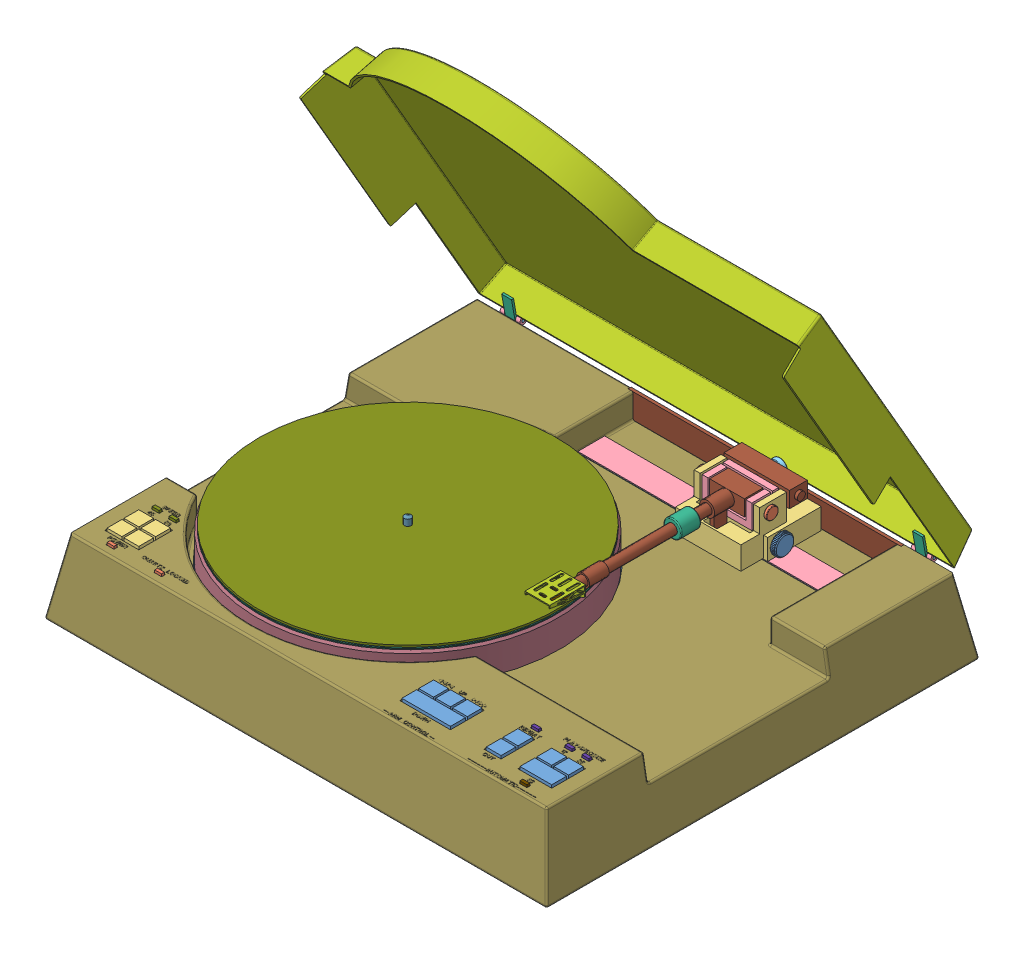
SolidWorks assembly Aptilla_Yamaha_PX-2, configuration Default. Lengths in mm.
Overall size (505.68 446.22 450.35).
80 component instances, 47 part files, 0 mates.
Components (placement in the parent):
- 05_ToneArm_Drive-1: 05_ToneArm_Drive [Default] at origin size (332.22 49 92)
  - 01_Carrier-1: 01_Carrier [Default] at origin size (321 49 83)
    - Roller.1.2-1: Roller.1.2 [Default] at (-301 0 0) size (19 19 29)
    - Roller.1.2-2: Roller.1.2 [Default] at origin size (19 19 29)
    - Roller.1.2-3: Roller.1.2 [Default] at (0 -20 0) size (19 19 29)
    - Roller.1.2-4: Roller.1.2 [Default] at (-301 -20 0) size (19 19 29)
    - Bracket.2-1: Bracket.2 [Default] at (175 0 0) size (20 36.5 33)
    - Wheel.2-1: Wheel.2 [Default] at (118 0 0) size (12 12 5)
    - Wheel.2-2: Wheel.2 [Default] at (248 58.6314 -492.1127) x (1 0 0) z (0 0 -1) size (12 12 5)
    - Wheel.2-3: Wheel.2 [Default] at (248 58.6314 -538.1127) x (1 0 0) z (0 0 -1) size (12 12 5)
    - Belt-1: Belt [Default] at origin size (318 37 27)
    - Carrier-1: Carrier [Default] at (258 0 0) size (150 43.5 64)
    - Wheel.2-4: Wheel.2 [Default] at (118 0 46) size (12 12 5)
    - RailProfile-1: RailProfile [Default] at origin size (321 12.5 83)
  - 02_Drive-1: 02_Drive [Default] at origin size (40.22 41 68)
    - Bracket.1-1: Bracket.1 [Default] at (-126 0 0) size (24 36.5 66)
    - Motor-1: Motor [Default] at origin size (40.22 22 22)
    - Gear.1-1: Gear.1 [Default] at (0 0 1) size (19 19 4)
    - Band-1: Band [Default] at origin size (1.5 20 35)
    - Worm_Axle-1: Worm_Axle [Default] at (10 -2 0) size (30 3 3)
    - Wheel_C-1: Wheel_C [Default] at (-0.5 0 0) size (8 10 10)
    - Axle.1-1: Axle.1 [Default] at origin size (2 2 40)
    - Worm-1: Worm [Default] at (10 -2 0) size (10 6 6)
    - Wheel_B-1: Wheel_B [Default] at (-0.5 0 0) size (4 20 20)
- 02_Controls-1: 02_Controls [Default] at origin size (452 6 60)
  - Controls_B.1-1: Controls_B.1 [Default] at (0 -6 0) size (44.81 6 9.25)
  - Controls_B.3-1: Controls_B.3 [Default] at (0 -6 0) size (155 6 9.25)
  - Controls_B.4-1: Controls_B.4 [Default] at (0 -6 0) size (155 6 9.25)
  - Controls_A.2-1: Controls_A.2 [Default] at (0 -6 0) size (155 6 41.5)
  - Controls_B.2-1: Controls_B.2 [Default] at (0 -6 0) size (71 6 9.25)
  - Controls_A.1-1: Controls_A.1 [Default] at (0 -6 0) size (71 6 41.5)
- 01_Base-1: 01_Base [Default] at origin size (505.68 446.22 450.35)
  - Hinge.1-1: Hinge.1 [Default] at (22 0 0) size (20 39.74 10.42)
    - Hinge_A-1: Hinge_A [Default] at origin size (20 23.8 7)
    - HingePin-1: HingePin [Default] at origin size (20 3 3)
    - Hinge_B-1: Hinge_B [Default] at origin size (10 22.94 10.42)
  - Cover-1: Cover [Default] at (0 298.2735 -73.3934) x (1 0 0) z (0 0.866025 0.5) size (488.72 54.66 402)
  - Support.1-1: Support.1 [Default] at (410 0 85) size (41.04 31.47 41.04)
    - Foot-1: Foot [Default] at (271.8949 582.3157 -214.5011) x (0 -1 0) z (1 0 0) size (31.47 41.04 41.04)
    - Spring-1: Spring [Default] at origin size (28.77 18.41 28.97)
  - Support.1-2: Support.1 [Default] at (410 0 340) size (41.04 31.47 41.04)
    - Foot-1: Foot [Default] at (271.8949 582.3157 -214.5011) x (0 -1 0) z (1 0 0) size (31.47 41.04 41.04)
    - Spring-1: Spring [Default] at origin size (28.77 18.41 28.97)
  - Support.1-3: Support.1 [Default] at (0 0 340) size (41.04 31.47 41.04)
    - Foot-1: Foot [Default] at (271.8949 582.3157 -214.5011) x (0 -1 0) z (1 0 0) size (31.47 41.04 41.04)
    - Spring-1: Spring [Default] at origin size (28.77 18.41 28.97)
  - Support.1-4: Support.1 [Default] at origin size (41.04 31.47 41.04)
    - Foot-1: Foot [Default] at (271.8949 582.3157 -214.5011) x (0 -1 0) z (1 0 0) size (31.47 41.04 41.04)
    - Spring-1: Spring [Default] at origin size (28.77 18.41 28.97)
  - Bottom-1: Bottom [Default] at origin size (474 26.57 402)
  - Plate-1: Plate [Default] at (0 -49.3225 -19.2435) x (1 0 0) z (0 -0.173648 0.984808) size (275 30.53 3)
  - Base_2-1: Base_2 [Default] at origin size (505.68 76.03 435.77)
  - Hinge.1-2: Hinge.1 [Default] at (-392 0 0) size (20 39.74 10.42)
    - Hinge_A-1: Hinge_A [Default] at origin size (20 23.8 7)
    - HingePin-1: HingePin [Default] at origin size (20 3 3)
    - Hinge_B-1: Hinge_B [Default] at origin size (10 22.94 10.42)
- 03_Turntable-1: 03_Turntable [Default] at (406.8949 615.896 105.9989) x (0 -1 0) z (1 0 0) size (81.31 304 304)
  - Turntable-1: Turntable [Default] at origin size (33 304 304)
  - Axle-1: Axle [Default] at origin size (81.31 6.86 6.86)
  - Mat-1: Mat [Default] at (890.3949 482.5 -406.8949) x (0 0 1) z (0 -1 0) size (300 2 300)
  - MusicDisc-1: MusicDisc [Default] at (522.2252 -15.5 176) x (0 0 -1) z (1 0 0) size (300 300 2)
  - Drive-1: Drive [Default] at (28 157.5 157.5) x (1 0 0) z (0 1 0) size (52.77 110.86 110.86)
    - Motor_Rotor-1: Motor_Rotor [Default] at (0 157.5 -157.5) x (1 0 0) z (0 -1 0) size (40.67 110.86 110.86)
    - Motor_Stator-1: Motor_Stator [Default] at (0 157.5 -157.5) x (1 0 0) z (0 -1 0) size (29.77 82.97 82.97)
- 04_Tone_Arm-1: 04_Tone_Arm [Default] at origin size (85 48.5 249)
  - Knob.1-1: Knob.1 [Default] at (1104.2898 2.5 -488.1127) x (-1 0 0) z (0 0 -1) size (15 19.96 20)
  - Knob.1-2: Knob.1 [Default] at (-0.5 2.5 0) size (15 19.96 20)
  - HingPin.2-1: HingPin.2 [Default] at (1103.7898 0 -475.1127) x (-1 0 0) z (0 0 -1) size (17.5 12 12)
  - HingPin.2-2: HingPin.2 [Default] at origin size (17.5 12 12)
  - Base-1: Base [Default] at origin size (74 47 77)
  - Block-1: Block [Default] at (-162 0 0) size (50 24 27)
  - Tone_arm-1: Tone_arm [Default] at origin size (72 33.5 244.5)
    - Weight-1: Weight [Default] at (789.4513 0.5 308.8386) x (0 0 -1) z (1 0 0) size (19.5 16 16)
    - Tube_Weight-1: Tube_Weight [Default] at (0 0 -100) size (18 18 20)
    - Bracket-1: Bracket [Default] at origin size (25 14 36)
    - Element-1: Element [Default] at (194.418 86.2072 120.8597) x (1 0 0) z (0 1 0) size (10 27.52 13.64)
      - Needle-1: Needle [Default] at origin size (1.46 6.25 3.18)
      - House-1: House [Default] at (-194.418 123.0355 -85.6815) x (1 0 0) z (0 -1 0) size (10 12 27.52)
      - Connector-1: Connector [Default] at (-194.418 120.8597 -86.2072) x (1 0 0) z (0 -1 0) size (6 5 7.93)
    - Arm-1: Arm [Default] at (-242 0 0) size (72 32 203)
